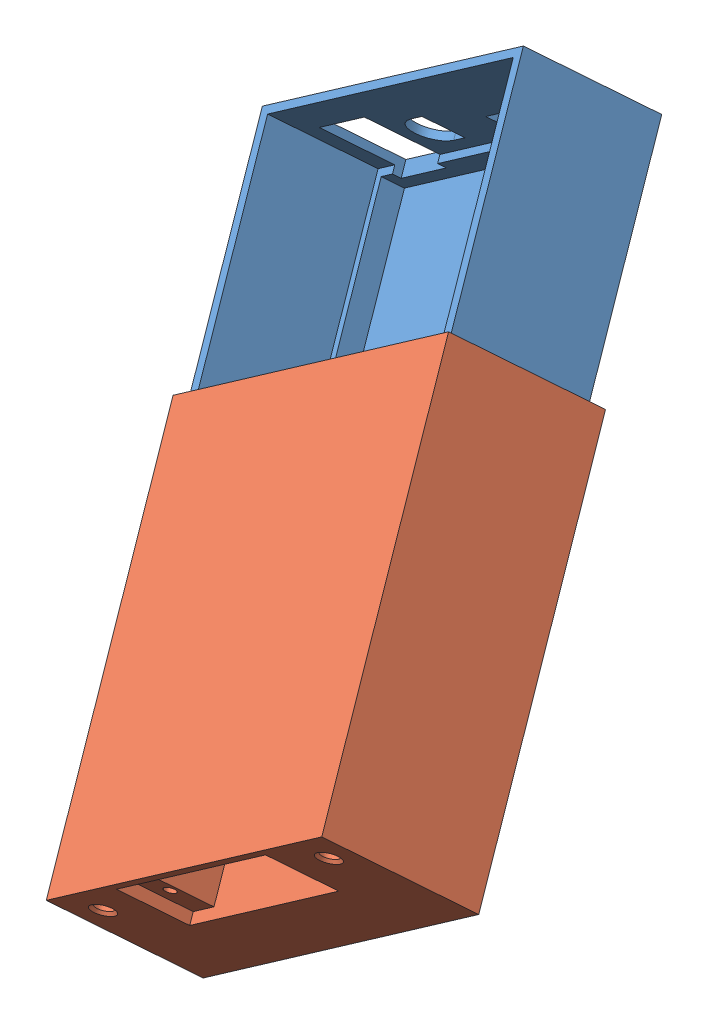
SolidWorks assembly 装配体2, configuration Default. Lengths in mm.
Overall size (105.51 113.15 103.64).
2 component instances, 2 part files, 1 mates.
Components (placement in the parent):
- ArdEspWiBox-1: ArdEspWiBox [默认] at (-230.1566 -9.6757 170.9161) x (0.403046 -0.554711 0.727908) z (-0.822296 -0.568636 0.021973) size (70 25.5 57.8)
- ServoVox-1: ServoVox [默认] at (-219.9863 -22.6372 216.09) x (0.401726 -0.607412 -0.685323) z (0.403046 -0.554711 0.727908) size (27 61 73)
Mates (geometry in assembly coordinates):
- 同心1: concentric anti-aligned: cylinder of ArdEspWiBox-1 through (-203.1306 -3.5446 203.2118) axis (0.403046 -0.554711 0.727908) radius 1; cylinder of ServoVox-1 through (-181.9017 -32.762 241.5517) axis (-0.403046 0.554711 -0.727908) radius 1.5
